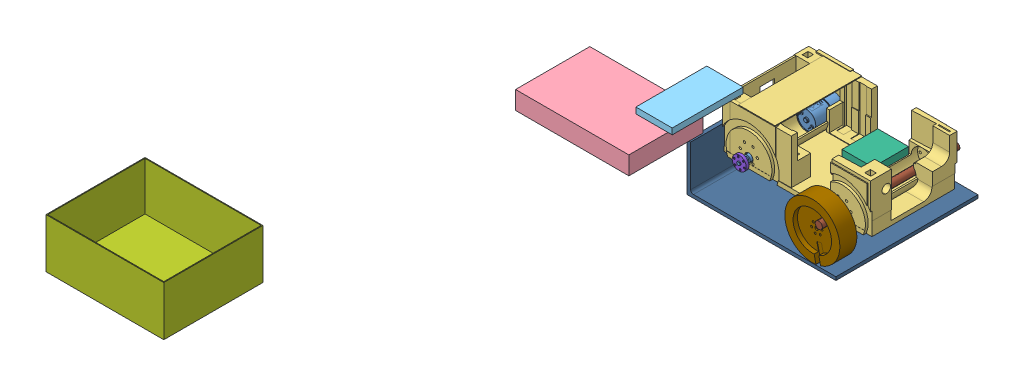
SolidWorks assembly BodyWithAxil, configuration Default. Lengths in mm.
Overall size (420.88 274.28 461.19).
14 component instances, 12 part files, 38 mates.
Components (placement in the parent):
- Pololu37DGearMotor-1: Pololu37DGearMotor [Default] at (449.967 24.575 -2152.8686) x (-1 0 0) z (0 0 -1) size (36.8 36.8 107.9)
- Pololu37DGearMotor-2: Pololu37DGearMotor [Default] at (410.117 24.575 -2038.7186) size (36.8 36.8 107.9)
- Part2-1: Part2 [Default] at origin
- RaspberryPi3-1: RaspberryPi3 [Default] at (547.1348 10.1 -2110.1682) x (0 0 1) z (0 1 0) size (89.64 57.31 18.92) (hidden)
- Chassis3-1: Chassis3 [Default] at (600.042 24.575 -2095.7936) x (-1 0 0) z (0 0 1) size (295.52 97.94 160.65)
- MaxoakPowerBank-1: MaxoakPowerBank [Default] at (250.8001 124.5785 -1906.0153) x (0 0 1) z (-1 0 0) size (135 33 206)
- MotoX-1: MotoX [Default] at (449.4488 208.455 -1791.0614) size (66.04 10.84 128.96)
- AdafruitMotorHat-1: AdafruitMotorHat [Default] at (577.5455 37.34 -2158.6101) x (0 0 1) z (1 0 0) size (65 13 56)
- Cover-1: Cover [Default] at (-302.6975 -256.127 -1471.0702) size (214.11 90 180) (hidden)
- PololuHub-2: PololuHub [Default] at (430.0421 17.575 -2190.7936) x (-0.300118 -0.953902 0) z (0 0 1) size (25.4 25.4 9.2)
- PololuHub-4: PololuHub [Default] at (430.042 17.5751 -2000.7936) x (-0.982388 -0.186853 0) z (0 0 -1) size (25.4 25.4 9.2)
- Wheel-3: Wheel [Default] at (586.4845 1.0178 -2005.6219) x (0 0 1) z (-1 0 0) size (30.86 100 100)
- ChargingDock-2: ChargingDock [Default] at (621.4227 -54.9822 -2210.9825) size (270.89 86 258.22)
- Axil-1: Axil [Default] at (600.042 17.575 -2097.8894) x (0 0 -1) z (-0.947994 0.318288 0) size (250 13.05 13.05)
Mates (geometry in assembly coordinates):
- Coincident2: coincident anti-aligned: line of Pololu37DGearMotor-1 through (430.042 17.575 -2172.7936) axis (0 0 -1); line of Pololu37DGearMotor-2 through (430.042 17.575 -2018.7936) axis (0 0 1)
- Coincident8: coincident anti-aligned: line of ? through (582.8805 17.575 -2172.7936) axis (0 0 -1); line of ? through (582.8805 17.575 -2018.7936) axis (0 0 1)
- Coincident9: coincident aligned: line of ? through (582.8805 24.575 -2118.4936) axis (0 0 1); line of Chassis3-1 through (582.8805 24.575 -2095.7936) axis (0 0 1)
- Coincident10: coincident anti-aligned: line of ? through (582.8805 24.575 -2073.0936) axis (0 0 -1); line of Chassis3-1 through (582.8805 24.575 -2095.7936) axis (0 0 1)
- Coincident11: coincident aligned: line of Pololu37DGearMotor-1 through (430.042 24.575 -2118.4936) axis (0 0 1); line of Chassis3-1 through (430.042 24.575 -2095.7936) axis (0 0 1)
- Coincident12: coincident anti-aligned: line of Pololu37DGearMotor-2 through (430.042 24.575 -2073.0936) axis (0 0 -1); line of Chassis3-1 through (430.042 24.575 -2095.7936) axis (0 0 1)
- Distance1: distance = 27.57 mm anti-aligned: plane of RaspberryPi3-1 through (577.5455 9.77 -2073.686) normal (0 -1 0); plane of AdafruitMotorHat-1 through (577.5455 37.34 -2158.6101) normal (0 1 0)
- Coincident17: coincident aligned: plane of RaspberryPi3-1 through (577.5455 9.34 -2076.676) normal (1 0 0); plane of AdafruitMotorHat-1 through (577.5455 24.34 -2158.6101) normal (1 0 0)
- Coincident18: coincident aligned: plane of RaspberryPi3-1 through (574.5555 9.34 -2158.6101) normal (0 0 -1); plane of AdafruitMotorHat-1 through (577.5455 24.34 -2158.6101) normal (0 0 -1)
- Parallel4: parallel aligned: plane of MaxoakPowerBank-1 through (456.8001 157.5785 -1906.0153) normal (1 0 0); plane of assembly through (0 0 0) normal (1 0 0)
- Parallel5: parallel anti-aligned: plane of Chassis3-1 through (600.042 24.575 -2175.7936) normal (0 0 -1); plane of assembly through (0 0 0) normal (0 0 1)
- Coincident33: coincident: point of ?; line of Chassis3-1 through (582.8805 17.575 -2095.7936) axis (0 0 1)
- Coincident34: coincident anti-aligned: line of Pololu37DGearMotor-1 through (430.042 17.575 -2172.7936) axis (0 0 -1); line of PololuHub-2 through (430.042 17.575 -2199.6436) axis (0 0 1)
- Coincident35: coincident anti-aligned: line of Pololu37DGearMotor-2 through (430.042 17.575 -2018.7936) axis (0 0 1); line of PololuHub-4 through (430.042 17.575 -1991.9436) axis (0 0 -1)
- Coincident36: coincident anti-aligned: line of ? through (582.8805 17.575 -2018.7936) axis (0 0 1); line of ? through (582.8805 17.575 -1991.9436) axis (0 0 -1)
- Coincident38: coincident anti-aligned: plane of Chassis3-1 through (515.042 0 -2095.7936) normal (0 -1 0); plane of assembly through (0 0 0) normal (0 1 0)
- Coincident39: coincident anti-aligned: line of ? through (582.8805 17.575 -2194.7936) axis (0 0 -1); line of ? through (582.8805 17.575 -2199.6436) axis (0 0 1)
- Parallel6: parallel aligned: plane of Pololu37DGearMotor-1; plane of assembly through (0 0 0) normal (0 1 0)
- Coincident41: coincident anti-aligned: plane of ? through (582.8805 24.575 -2172.7936) normal (0 0 -1); plane of Chassis3-1 through (582.8805 24.575 -2172.7936) normal (0 0 1)
- Coincident42: coincident anti-aligned: plane of ? through (582.8805 24.575 -2018.7936) normal (0 0 1); plane of Chassis3-1 through (582.8805 24.575 -2018.7936) normal (0 0 -1)
- Coincident43: coincident anti-aligned: plane of Pololu37DGearMotor-1 through (430.042 24.575 -2172.7936) normal (0 0 -1); plane of Chassis3-1 through (430.042 24.575 -2172.7936) normal (0 0 1)
- Coincident44: coincident anti-aligned: plane of Pololu37DGearMotor-2 through (430.042 24.575 -2018.7936) normal (0 0 1); plane of Chassis3-1 through (430.042 24.575 -2018.7936) normal (0 0 -1)
- Distance3: distance = 1.5 mm aligned: plane of ? through (582.8805 17.575 -1998.2936) normal (0 0 1); plane of ? through (582.8805 17.575 -1996.7936) normal (0 0 1)
- Distance4: distance = 1.5 mm aligned: plane of PololuHub-4 through (430.042 17.575 -1998.2936) normal (0 0 1); plane of Pololu37DGearMotor-2 through (430.042 17.575 -1996.7936) normal (0 0 1)
- Distance5: distance = 1.5 mm aligned: plane of ? through (582.8805 17.575 -2193.2936) normal (0 0 -1); plane of ? through (582.8805 17.575 -2194.7936) normal (0 0 -1)
- Distance6: distance = 1.5 mm aligned: plane of PololuHub-2 through (430.042 17.575 -2193.2936) normal (0 0 -1); plane of Pololu37DGearMotor-1 through (430.042 17.575 -2194.7936) normal (0 0 -1)
- Perpendicular1: perpendicular: plane of ? through (582.8805 19.975 -2182.7936) normal (0 1 0); line of ? through (582.8805 29.925 -2186.1936) axis (0 -1 0)
- Parallel11: parallel: plane of ? through (582.8805 19.975 -2182.7936) normal (0 1 0); line of ? through (592.4105 17.575 -2216.1536) axis (-1 0 0)
- Coincident54: coincident anti-aligned: plane of ? through (582.8805 17.575 -2193.2936) normal (0 0 -1); plane of ? through (582.8805 17.575 -2193.2936) normal (0 0 1)
- Concentric1: concentric anti-aligned: cylinder of ? through (582.8805 17.575 -2188.2936) axis (0 0 -1) radius 12.7; cylinder of ? through (582.8805 17.575 -2195.2936) axis (0 0 1) radius 3.2
- Concentric2: concentric aligned: circle of ?; cylinder of ? through (587.6455 9.3218 -2187.6736) axis (0 0 -1) radius 1.335
- Coincident55: coincident anti-aligned: plane of ? through (587.6455 9.3218 -2206.1536) normal (0 0 -1); plane of ? through (587.6455 9.3218 -2206.1536) normal (0 0 1)
- Concentric3: concentric anti-aligned: cylinder of ? through (582.8805 17.575 -2012.2936) axis (0 0 -1) radius 6; cylinder of Wheel-3 through (582.8805 17.575 -1907.5253) axis (0 0 1) radius 3.2
- Tangent1: tangent anti-aligned: cylinder of Wheel-3 through (586.4845 1.0178 -1974.7619) axis (0 0 -1) radius 50; plane of ChargingDock-2 through (621.4227 -48.9822 -2210.9825) normal (0 1 0)
- Parallel12: parallel aligned: plane of ChargingDock-2 through (621.4227 -48.9822 -2210.9825) normal (0 1 0); plane of assembly through (0 0 0) normal (0 1 0)
- Coincident56: coincident anti-aligned: plane of RaspberryPi3-1 through (574.9874 8 -2148.344) normal (0 -1 0); plane of Chassis3-1 through (515.042 8 -2095.7936) normal (0 1 0)
- Concentric5: concentric aligned: cylinder of RaspberryPi3-1 through (574.0455 11.1 -2097.1101) axis (0 1 0) radius 3; cylinder of Chassis3-1 through (574.0455 -2 -2097.1101) axis (0 1 0) radius 1.1452
- Concentric6: concentric anti-aligned: cylinder of Chassis3-1 through (600.042 17.575 -2047.2936) axis (0 0 1) radius 7.5; cylinder of Axil-1 through (600.042 17.575 -1972.8894) axis (0 0 -1) radius 6.523
